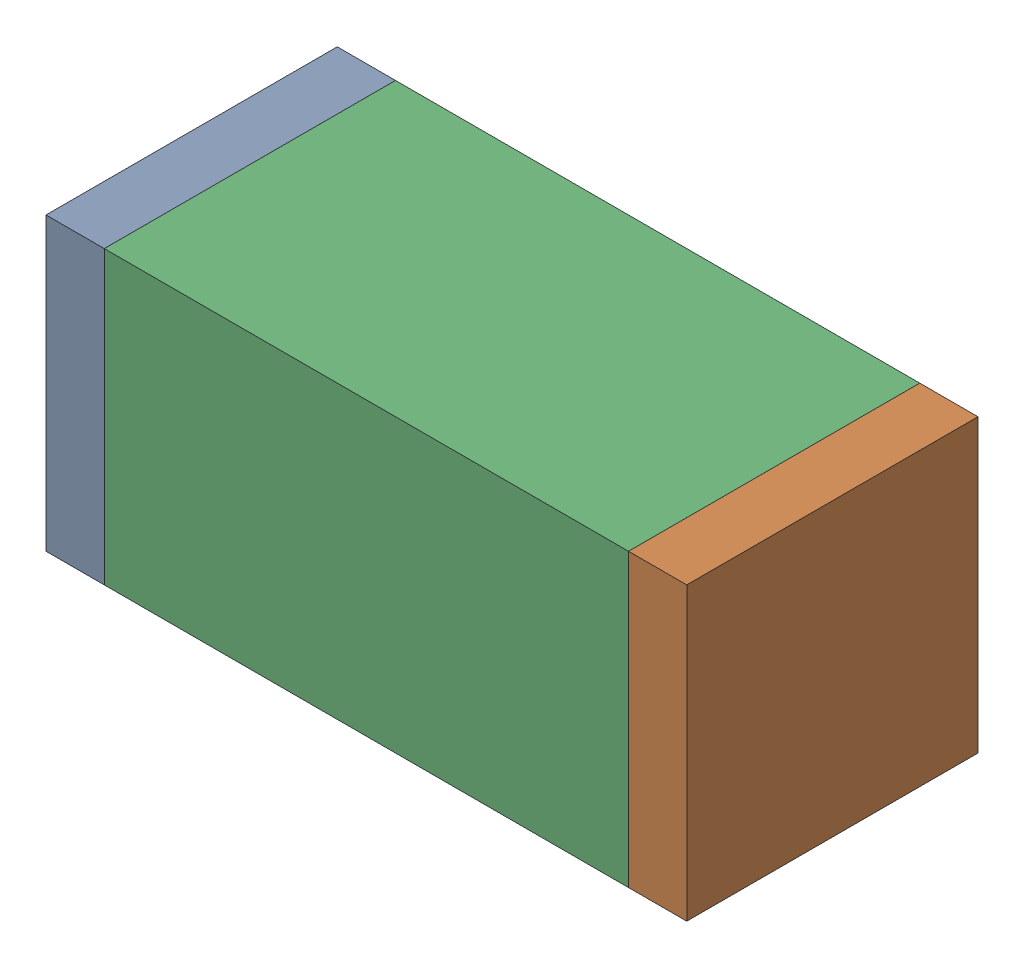
SolidWorks assembly C78, configuration Default. Lengths in mm.
Overall size (1.1 0.5 0.5).
6 component instances, 2 part files, 0 mates.
Components (placement in the parent):
- 810156080-1: 810156080 [Default] at (117.65 60.95 0) size (0.1 0.5 0.5)
  - Extruded_5-1: Extruded_5 [Default] at origin size (0.1 0.5 0.5)
- 810156080-2: 810156080 [Default] at (118.65 60.95 0) size (0.1 0.5 0.5)
  - Extruded_5-1: Extruded_5 [Default] at origin size (0.1 0.5 0.5)
- 836749680-1: 836749680 [Default] at (118.15 60.95 0) size (0.9 0.5 0.5)
  - Extruded_4-1: Extruded_4 [Default] at origin size (0.9 0.5 0.5)
